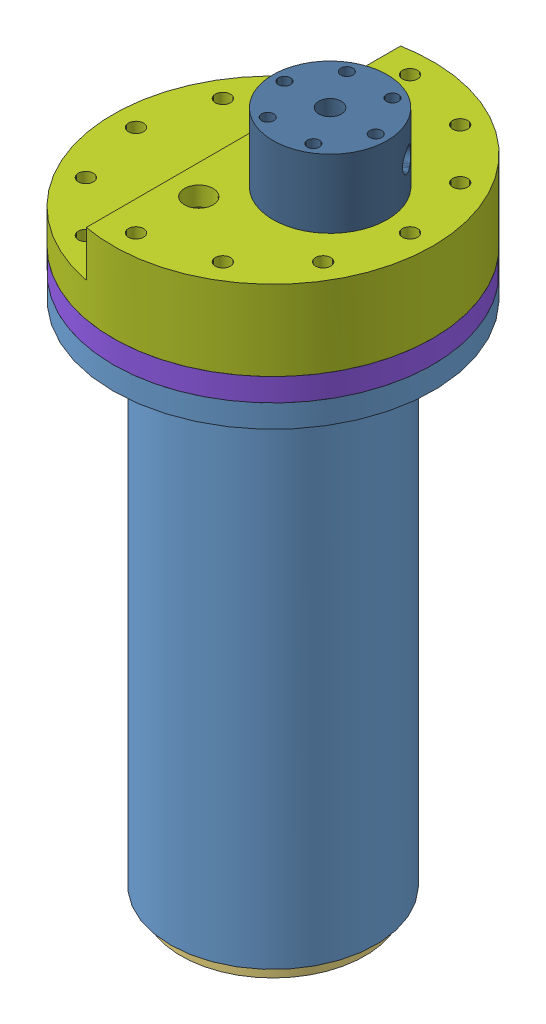
SolidWorks assembly APL1_firstEngineTest5, configuration Default. Lengths in mm.
Overall size (217.76 398.89 217.76).
10 component instances, 10 part files, 22 mates.
Components (placement in the parent):
- APL1_OuterChamberCasing-1: APL1_OuterChamberCasing [Default] at origin size (177.8 295.28 177.8)
- APL1_ablativeInsert-1: APL1_ablativeInsert [Default] at (0 -3.175 0) x (0.966975 0 -0.25487) z (0.25487 0 0.966975) size (102.26 152.4 102.26)
- APL1_graphiteInsert-1: APL1_graphiteInsert [Default] at (0 -155.575 0) x (0.995497 0 -0.094792) z (0.094792 0 0.995497) size (102.26 148.07 102.26)
- APL1_Dowel2_1-1: APL1_Dowel2_1 [Default] at (-12.3733 -4.5095 -7.1437) x (0.800915 0 -0.598778) z (0.598778 0 0.800915) size (3.17 28.57 3.17)
- APL1_LowerInjectorPlate5-1: APL1_LowerInjectorPlate5 [Default] at (0 -3.175 0) x (-1 0 0) z (0 0 -1) size (114.3 6.63 114.3)
- APL1_TopInjectorPlate5-1: APL1_TopInjectorPlate5 [Default] at (0 12.7 0) x (-0.47896 0 -0.877837) z (0.877837 0 -0.47896) size (41.27 24.77 41.27)
- APL1_dome5-1: APL1_dome5 [Default] at (0 12.7 0) x (0.965926 0 0.258819) z (-0.258819 0 0.965926) size (177.8 44.45 177.8)
- APL1_manifoldSpacerBlock5-1: APL1_manifoldSpacerBlock5 [Default] at origin size (177.8 12.7 177.8)
- APL1_ignitorCore5-1: APL1_ignitorCore5 [Default] at (31.75 63.5 0) size (25.4 69.85 25.4)
- APL1_ignitor5-1: APL1_ignitor5 [Default] at (31.75 63.5 0) x (0.866025 0 -0.5) z (0.5 0 0.866025) size (63.5 38.1 63.5)
Mates (geometry in assembly coordinates):
- Concentric5: concentric aligned: cylinder of APL1_OuterChamberCasing-1 through (0 0 0) axis (0 1 0) radius 51.1302; cylinder of APL1_ablativeInsert-1 through (0 -3.175 0) axis (0 1 0) radius 51.1302
- Concentric6: concentric aligned: cylinder of APL1_OuterChamberCasing-1 through (0 0 0) axis (0 1 0) radius 51.1302; cylinder of APL1_graphiteInsert-1 through (0 -155.575 0) axis (0 1 0) radius 51.1302
- Coincident7: coincident anti-aligned: plane of APL1_ablativeInsert-1 through (-36.8418 -155.575 9.7106) normal (0 -1 0); plane of APL1_graphiteInsert-1 through (-44.5786 -155.575 4.2448) normal (0 1 0)
- Coincident8: coordinate: point of APL1_OuterChamberCasing-1
- Coincident9: coincident aligned: plane of APL1_OuterChamberCasing-1 through (-51.1302 -3.175 0) normal (0 1 0); plane of APL1_ablativeInsert-1 through (-36.8418 -3.175 9.7106) normal (0 1 0)
- Concentric16: concentric anti-aligned: cylinder of APL1_OuterChamberCasing-1 through (0 0 0) axis (0 1 0) radius 57.15; cylinder of APL1_LowerInjectorPlate5-1 through (0 -3.175 0) axis (0 -1 0) radius 57.15
- Concentric17: concentric anti-aligned: cylinder of APL1_Dowel2_1-1 through (-12.3733 24.0655 -7.1437) axis (0 -1 0) radius 1.5875; cylinder of APL1_LowerInjectorPlate5-1 through (-12.3733 3.175 -7.1437) axis (0 1 0) radius 1.5875
- Coincident13: coincident anti-aligned: plane of APL1_OuterChamberCasing-1 through (-51.1302 -3.175 0) normal (0 1 0); plane of APL1_LowerInjectorPlate5-1 through (0 -3.175 0) normal (0 -1 0)
- Concentric19: concentric anti-aligned: cylinder of APL1_OuterChamberCasing-1 through (0 0 0) axis (0 1 0) radius 57.15; cylinder of APL1_TopInjectorPlate5-1 through (0 12.7 0) axis (0 -1 0) radius 20.6375
- Concentric21: concentric anti-aligned: cylinder of APL1_OuterChamberCasing-1 through (0 0 0) axis (0 1 0) radius 88.9; cylinder of APL1_dome5-1 through (0 12.7 0) axis (0 -1 0) radius 88.9
- Concentric22: concentric aligned: cylinder of APL1_OuterChamberCasing-1 through (-65.9911 0 38.1) axis (0 1 0) radius 4.2164; cylinder of APL1_dome5-1 through (-65.9911 57.15 38.1) axis (0 1 0) radius 4.2164
- Coincident14: coincident anti-aligned: plane of APL1_TopInjectorPlate5-1 through (9.3067 19.05 17.0572) normal (0 1 0); plane of APL1_dome5-1 through (-13.8007 19.05 -3.6979) normal (0 -1 0)
- Concentric24: concentric aligned: cylinder of APL1_OuterChamberCasing-1 through (0 0 0) axis (0 1 0) radius 88.9; cylinder of APL1_manifoldSpacerBlock5-1 through (0 12.7 0) axis (0 1 0) radius 88.9
- Coincident15: coincident anti-aligned: plane of APL1_dome5-1 through (-52.5039 12.7 -14.0684) normal (0 -1 0); plane of APL1_manifoldSpacerBlock5-1 through (-88.9 12.7 0) normal (0 1 0)
- Coincident16: coincident anti-aligned: plane of APL1_OuterChamberCasing-1 through (-57.15 0 0) normal (0 1 0); plane of APL1_manifoldSpacerBlock5-1 through (0 0 0) normal (0 -1 0)
- Concentric26: concentric aligned: cylinder of APL1_LowerInjectorPlate5-1 through (31.75 3.175 0) axis (0 1 0) radius 5.08; cylinder of APL1_dome5-1 through (31.75 57.15 0) axis (0 1 0) radius 5.08
- Concentric27: concentric aligned: cylinder of APL1_OuterChamberCasing-1 through (76.2 0 0) axis (0 1 0) radius 4.2164; cylinder of APL1_manifoldSpacerBlock5-1 through (76.2 12.7 0) axis (0 1 0) radius 4.2164
- Concentric31: concentric aligned: cylinder of APL1_dome5-1 through (31.75 57.15 0) axis (0 1 0) radius 5.08; cylinder of APL1_ignitorCore5-1 through (31.75 63.5 0) axis (0 1 0) radius 5.08
- Coincident19: coincident anti-aligned: plane of APL1_dome5-1 through (-85.8708 57.15 -23.009) normal (0 1 0); plane of APL1_ignitorCore5-1 through (23.6855 57.15 0) normal (0 -1 0)
- Concentric32: concentric anti-aligned: cylinder of APL1_ignitorCore5-1 through (31.75 63.5 0) axis (0 1 0) radius 12.7; cylinder of APL1_ignitor5-1 through (31.75 63.5 0) axis (0 -1 0) radius 12.7
- Coincident20: coincident anti-aligned: plane of APL1_dome5-1 through (-85.8708 57.15 -23.009) normal (0 1 0); plane of APL1_ignitor5-1 through (4.2537 57.15 15.875) normal (0 -1 0)
- Concentric33: concentric aligned: cylinder of APL1_dome5-1 through (57.15 57.15 0) axis (0 1 0) radius 2.7051; cylinder of APL1_ignitor5-1 through (57.15 95.25 0) axis (0 1 0) radius 3.3782
